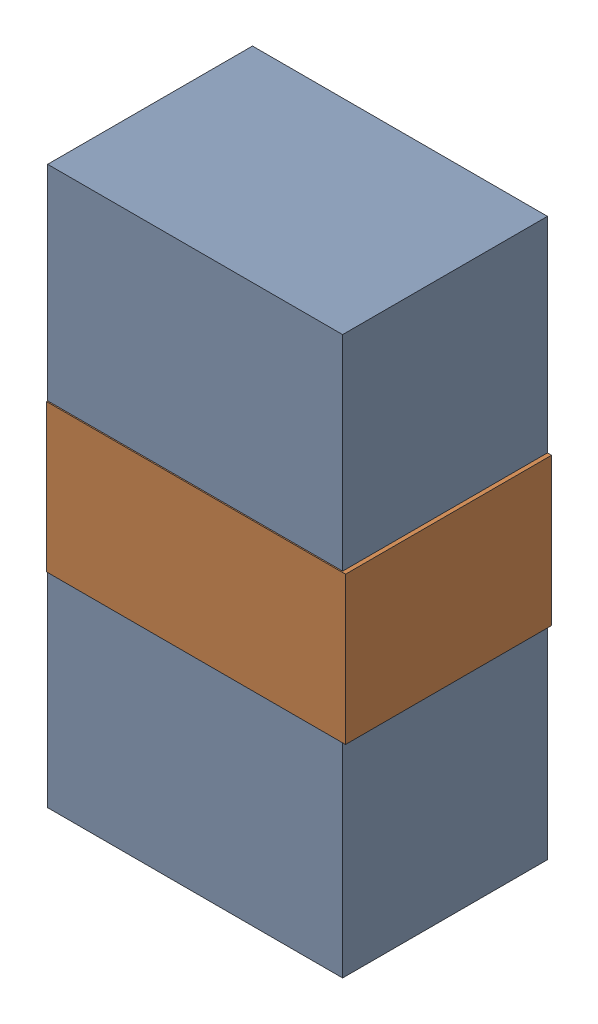
SolidWorks assembly LED2_Motor_9Kanaloa_v2.0.0_Motor, configuration Default. Lengths in mm.
Overall size (1.83 3.4 1.26).
4 component instances, 2 part files, 0 mates.
Components (placement in the parent):
- 334788016-1: 334788016 [Default] at (42.6005 173.482 0) size (1.8 3.4 1.25)
  - Extruded_12-1: Extruded_12 [Default] at origin size (1.8 3.4 1.25)
- 334787760-1: 334787760 [Default] at (42.613 173.482 0) size (1.83 0.9 1.26)
  - Extruded_13-1: Extruded_13 [Default] at origin size (1.83 0.9 1.26)
